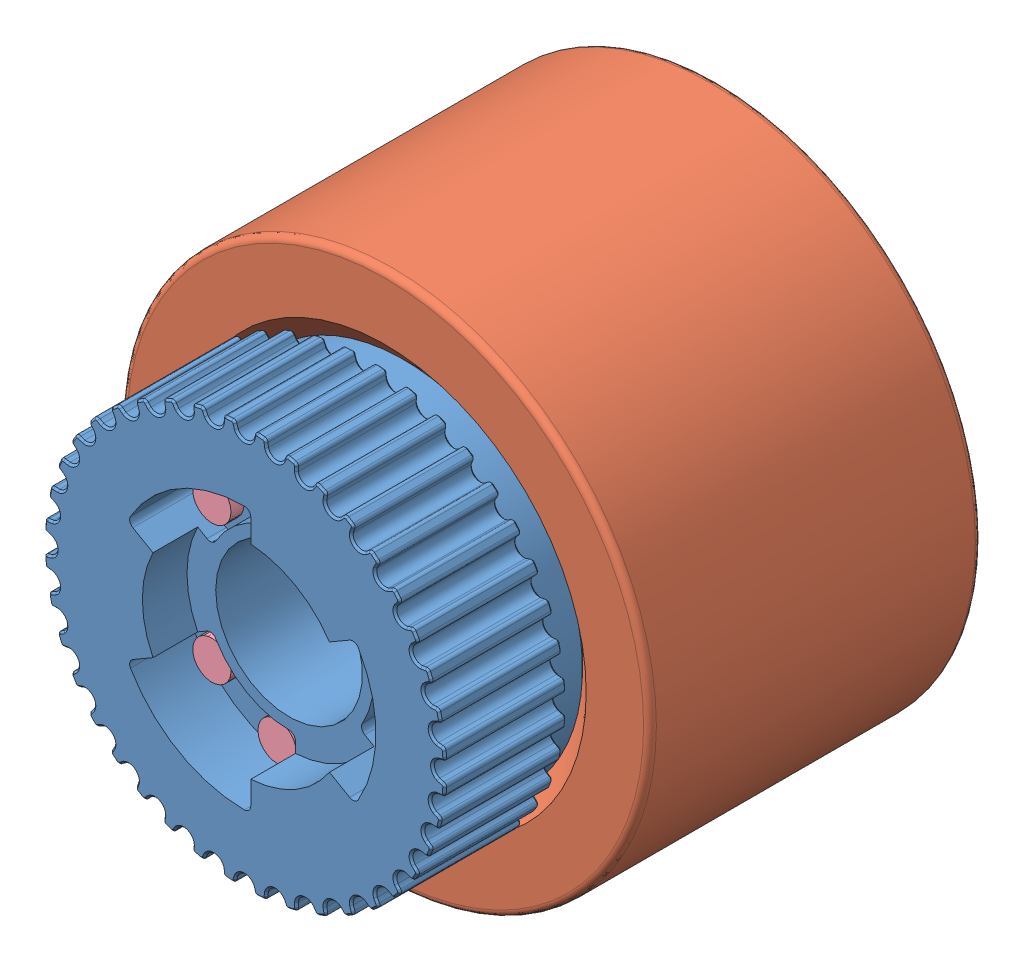
SolidWorks assembly Assem plastic hub, configuration Default. Lengths in mm.
Overall size (83 83 74.08).
9 component instances, 4 part files, 9 mates.
Components (placement in the parent):
- 40T 5MGT plastic-1: 40T 5MGT plastic [Default] at (0 0 29) x (0 -1 0) z (-1 0 0) size (62.8 35.18 62.8)
- 83mm wheel-1: 83mm wheel [Default] at origin size (83 83 52)
- M24 washer-1: M24 washer [Default] at (0 0 -18) x (1 0 0) z (0 1 0) size (44 2.5 44)
- long bolt-1: long bolt [Default] at (-2.8316 16.7064 -24.8731) x (0.824913 -0.56526 0) z (-0.56526 -0.824913 0) size (6 65 6)
- long bolt-2: long bolt [Default] at (-13.0524 10.8054 -24.8731) x (1 0 0) z (0 -1 0) size (6 65 6)
- long bolt-3: long bolt [Default] at (-13.0524 -10.8054 -24.8731) x (0.077073 0.997025 0) z (0.997025 -0.077073 0) size (6 65 6)
- long bolt-4: long bolt [Default] at (15.8839 -5.901 -24.8731) x (-0.901986 -0.431766 0) z (-0.431766 0.901986 0) size (6 65 6)
- long bolt-5: long bolt [Default] at (-2.8316 -16.7064 -24.8731) x (-0.5 0.866025 0) z (0.866025 0.5 0) size (6 65 6)
- long bolt-6: long bolt [Default] at (15.8839 5.901 -24.8731) x (-0.5 -0.866025 0) z (-0.866025 0.5 0) size (6 65 6)
Mates (geometry in assembly coordinates):
- Coincident1: coordinate: point of 83mm wheel-1; point of assembly
- Concentric1: concentric aligned: cylinder of 83mm wheel-1 through (0 0 -26) axis (0 0 1) radius 8.25; cylinder of 40T 5MGT plastic-1 through (0 0 41.08) axis (0 0 1) radius 16
- Coincident5: coincident anti-aligned: plane of 40T 5MGT plastic-1 through (0 0 29) normal (-1 0 0); plane of 83mm wheel-1 through (0 0 0) normal (1 0 0)
- Coincident6: coincident anti-aligned: circle of 83mm wheel-1; circle of M24 washer-1
- Concentric2: concentric anti-aligned: cylinder of 83mm wheel-1 through (0 0 -5.2) axis (0 0 -1) radius 11; cylinder of M24 washer-1 through (0 0 -20.5) axis (0 0 1) radius 12.5
- Distance3: distance = 3 mm anti-aligned: plane of 83mm wheel-1 through (0 0 26) normal (0 0 1); plane of 40T 5MGT plastic-1 through (0 0 29) normal (0 0 -1)
- Concentric3: concentric anti-aligned: cylinder of 40T 5MGT plastic-1 through (-2.8316 16.7064 12.9038) axis (0 0 1) radius 3; cylinder of long bolt-1 through (-2.8316 16.7064 40.1269) axis (0 0 -1) radius 3
- Concentric4: concentric anti-aligned: cylinder of 40T 5MGT plastic-1 through (-13.0524 10.8054 12.9038) axis (0 0 1) radius 3; cylinder of long bolt-2 through (-13.0524 10.8054 40.1269) axis (0 0 -1) radius 3
- Coincident9: coincident aligned: plane of long bolt-1 through (-2.8316 16.7064 40.1269) normal (0 0 1); plane of long bolt-2 through (-13.0524 10.8054 40.1269) normal (0 0 1)
